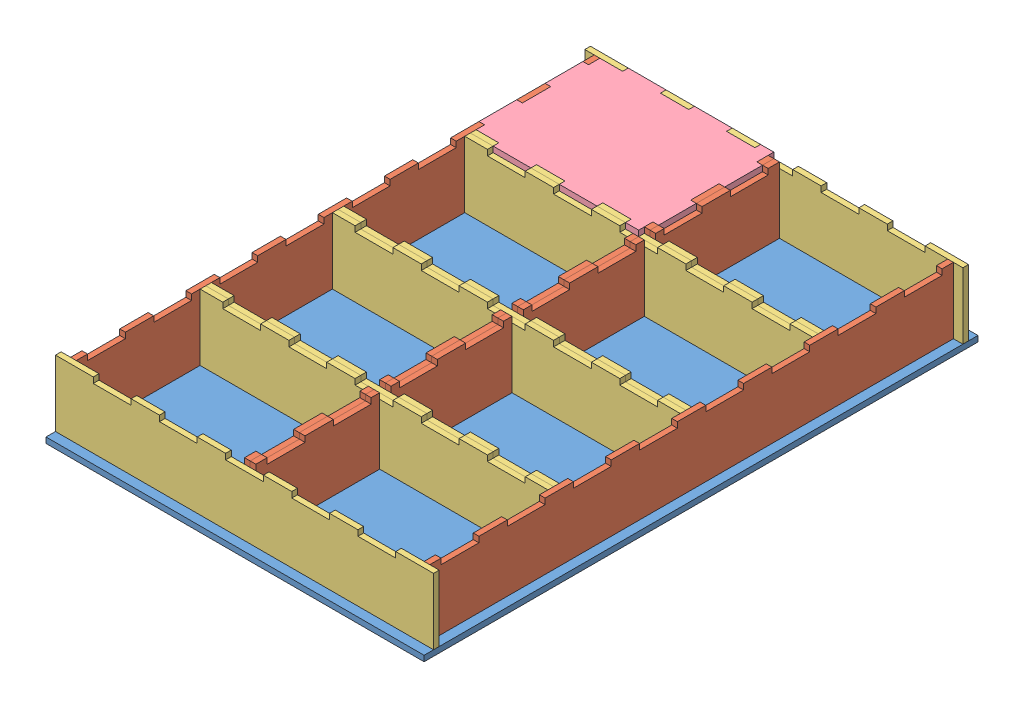
SolidWorks assembly Assem1, configuration Default. Lengths in mm.
Overall size (200 38 293).
20 component instances, 4 part files, 57 mates.
Components (placement in the parent):
- base-1: base [Default] at (16.4212 149.2181 390.9951) size (200 3 293)
- long_side-1: long_side [Default] at (21.4212 152.2181 382.9951) size (3 38 277)
- side-1: side [Default] at (16.4212 152.2181 102.9951) x (1 0 0) z (0 0 -1) size (200 38 3)
- long_side-2: long_side [Default] at (208.4212 152.2181 382.9951) size (3 38 277)
- side-2: side [Default] at (16.4212 152.2181 382.9951) x (1 0 0) z (0 0 -1) size (200 38 3)
- side-3: side [inside] at (208.4212 152.2181 177.4951) x (-1 0 0) z (0 0 1) size (184 38 3)
- side-4: side [inside] at (208.4212 152.2181 174.4951) x (-1 0 0) z (0 0 1) size (184 38 3)
- side-5: side [inside] at (208.4212 152.2181 314.4951) x (-1 0 0) z (0 0 1) size (184 38 3)
- side-6: side [inside] at (208.4212 152.2181 244.4951) x (-1 0 0) z (0 0 1) size (184 38 3)
- side-7: side [inside] at (24.4212 152.2181 244.4951) x (1 0 0) z (0 0 -1) size (184 38 3)
- side-8: side [inside] at (208.4212 152.2181 317.4951) x (-1 0 0) z (0 0 1) size (184 38 3)
- long_side-3: long_side [inside] at (113.4212 152.2181 382.9951) size (3 38 65.5)
- long_side-5: long_side [inside_middle] at (116.4212 152.2181 177.4951) x (-1 0 0) z (0 0 -1) size (3 38 64)
- long_side-7: long_side [inside_middle] at (116.4212 152.2181 241.4951) size (3 38 64)
- long_side-8: long_side [inside_middle] at (116.4212 152.2181 311.4951) size (3 38 64)
- long_side-9: long_side [inside_middle] at (113.4212 152.2181 311.4951) size (3 38 64)
- long_side-10: long_side [inside] at (116.4212 152.2181 382.9951) size (3 38 65.5)
- long_side-11: long_side [inside] at (116.4212 152.2181 105.9951) x (-1 0 0) z (0 0 -1) size (3 38 65.5)
- long_side-12: long_side [inside] at (119.4212 152.2181 105.9951) x (-1 0 0) z (0 0 -1) size (3 38 65.5)
- top-1: top [Default] at (24.4212 184.2181 171.4951) size (95 3 71.5)
Mates (geometry in assembly coordinates):
- Coincident2: coincident anti-aligned: plane of base-1 through (156.4212 142.2181 102.9951) normal (0 0 1); plane of side-1 through (16.4212 152.2181 102.9951) normal (0 0 -1)
- Coincident3: coincident aligned: plane of base-1 through (216.4212 152.2181 390.9951) normal (1 0 0); plane of side-1 through (216.4212 152.2181 105.9951) normal (1 0 0)
- Coincident4: coincident anti-aligned: plane of base-1 through (16.4212 152.2181 390.9951) normal (0 1 0); plane of side-1 through (196.4212 152.2181 105.9951) normal (0 -1 0)
- Coincident5: coincident anti-aligned: plane of base-1 through (24.4212 142.2181 460.9951) normal (-1 0 0); plane of long_side-1 through (24.4212 152.2181 382.9951) normal (1 0 0)
- Coincident6: coincident anti-aligned: plane of long_side-1 through (24.4212 152.2181 105.9951) normal (0 0 -1); plane of side-1 through (16.4212 152.2181 105.9951) normal (0 0 1)
- Coincident7: coincident aligned: plane of base-1 through (16.4212 149.2181 390.9951) normal (0 -1 0); plane of long_side-1 through (24.4212 149.2181 376.9951) normal (0 -1 0)
- Coincident9: coincident aligned: plane of base-1 through (216.4212 152.2181 390.9951) normal (1 0 0); plane of side-2 through (216.4212 152.2181 385.9951) normal (1 0 0)
- Coincident11: coincident aligned: plane of base-1 through (16.4212 149.2181 390.9951) normal (0 -1 0); plane of side-2 through (71.4212 149.2181 385.9951) normal (0 -1 0)
- Coincident14: coincident aligned: plane of base-1 through (16.4212 149.2181 390.9951) normal (0 -1 0); plane of long_side-2 through (211.4212 149.2181 131.9951) normal (0 -1 0)
- Coincident15: coincident anti-aligned: plane of side-1 through (16.4212 152.2181 105.9951) normal (0 0 1); plane of long_side-2 through (211.4212 152.2181 105.9951) normal (0 0 -1)
- Coincident16: coincident anti-aligned: plane of base-1 through (211.4212 142.2181 600.9951) normal (-1 0 0); plane of long_side-2 through (211.4212 152.2181 382.9951) normal (1 0 0)
- Coincident17: coincident anti-aligned: plane of base-1 through (16.4212 152.2181 390.9951) normal (0 1 0); plane of side-3 through (106.4212 152.2181 174.4951) normal (0 -1 0)
- Coincident18: coincident anti-aligned: plane of long_side-2 through (208.4212 152.2181 382.9951) normal (-1 0 0); plane of side-3 through (208.4212 152.2181 174.4951) normal (1 0 0)
- Coincident19: coincident anti-aligned: plane of base-1 through (36.4212 142.2181 177.4951) normal (0 0 -1); plane of side-3 through (208.4212 152.2181 177.4951) normal (0 0 1)
- Coincident20: coincident anti-aligned: plane of base-1 through (16.4212 152.2181 390.9951) normal (0 1 0); plane of side-4 through (208.4212 152.2181 171.4951) normal (0 -1 0)
- Coincident21: coincident anti-aligned: plane of side-3 through (208.4212 152.2181 174.4951) normal (0 0 -1); plane of side-4 through (208.4212 152.2181 174.4951) normal (0 0 1)
- Coincident22: coincident aligned: plane of side-3 through (106.4212 187.2181 174.4951) normal (0 1 0); plane of side-4 through (208.4212 187.2181 171.4951) normal (0 1 0)
- Coincident23: coincident anti-aligned: plane of long_side-2 through (208.4212 152.2181 382.9951) normal (-1 0 0); plane of side-4 through (208.4212 152.2181 171.4951) normal (1 0 0)
- Coincident24: coincident anti-aligned: plane of base-1 through (141.4212 142.2181 247.4951) normal (0 0 -1); plane of side-7 through (24.4212 152.2181 247.4951) normal (0 0 1)
- Coincident25: coincident anti-aligned: plane of base-1 through (16.4212 152.2181 390.9951) normal (0 1 0); plane of side-7 through (91.4212 152.2181 247.4951) normal (0 -1 0)
- Coincident26: coincident anti-aligned: plane of long_side-1 through (24.4212 152.2181 382.9951) normal (1 0 0); plane of side-7 through (24.4212 152.2181 247.4951) normal (-1 0 0)
- Coincident27: coincident aligned: plane of base-1 through (16.4212 149.2181 390.9951) normal (0 -1 0); plane of side-6 through (196.4212 149.2181 241.4951) normal (0 -1 0)
- Coincident28: coincident anti-aligned: plane of side-6 through (208.4212 152.2181 244.4951) normal (0 0 1); plane of side-7 through (24.4212 152.2181 244.4951) normal (0 0 -1)
- Coincident29: coincident anti-aligned: plane of long_side-2 through (208.4212 152.2181 382.9951) normal (-1 0 0); plane of side-6 through (208.4212 152.2181 241.4951) normal (1 0 0)
- Coincident30: coincident anti-aligned: plane of base-1 through (16.4212 152.2181 390.9951) normal (0 1 0); plane of side-5 through (176.4212 152.2181 311.4951) normal (0 -1 0)
- Coincident31: coincident anti-aligned: plane of long_side-2 through (208.4212 152.2181 382.9951) normal (-1 0 0); plane of side-5 through (208.4212 152.2181 311.4951) normal (1 0 0)
- Coincident32: coincident anti-aligned: plane of base-1 through (141.4212 142.2181 311.4951) normal (0 0 1); plane of side-5 through (208.4212 152.2181 311.4951) normal (0 0 -1)
- Coincident33: coincident anti-aligned: plane of base-1 through (16.4212 152.2181 390.9951) normal (0 1 0); plane of side-8 through (141.4212 152.2181 314.4951) normal (0 -1 0)
- Coincident34: coincident anti-aligned: plane of long_side-2 through (208.4212 152.2181 382.9951) normal (-1 0 0); plane of side-8 through (208.4212 152.2181 314.4951) normal (1 0 0)
- Coincident35: coincident anti-aligned: plane of side-5 through (208.4212 152.2181 314.4951) normal (0 0 1); plane of side-8 through (208.4212 152.2181 314.4951) normal (0 0 -1)
- Coincident37: coincident anti-aligned: plane of base-1 through (119.4212 142.2181 286.9951) normal (-1 0 0); plane of long_side-8 through (119.4212 152.2181 311.4951) normal (1 0 0)
- Coincident38: coincident anti-aligned: plane of side-7 through (24.4212 152.2181 247.4951) normal (0 0 1); plane of long_side-8 through (109.4212 192.2181 247.4951) normal (0 0 -1)
- Coincident39: coincident aligned: plane of base-1 through (16.4212 149.2181 390.9951) normal (0 -1 0); plane of long_side-8 through (119.4212 149.2181 271.9951) normal (0 -1 0)
- Coincident40: coincident anti-aligned: plane of long_side-7 through (119.4212 152.2181 241.4951) normal (1 0 0); plane of base-1 through (119.4212 142.2181 216.9951) normal (-1 0 0)
- Coincident41: coincident anti-aligned: plane of side-3 through (208.4212 152.2181 177.4951) normal (0 0 1); plane of long_side-7 through (109.4212 192.2181 177.4951) normal (0 0 -1)
- Coincident42: coincident aligned: plane of long_side-7 through (119.4212 187.2181 216.9951) normal (0 1 0); plane of long_side-8 through (119.4212 187.2181 286.9951) normal (0 1 0)
- Coincident43: coincident anti-aligned: plane of base-1 through (113.4212 142.2181 216.9951) normal (1 0 0); plane of long_side-9 through (113.4212 152.2181 311.4951) normal (-1 0 0)
- Coincident45: coincident aligned: plane of long_side-8 through (119.4212 184.2181 306.9951) normal (0 1 0); plane of long_side-9 through (116.4212 184.2181 306.9951) normal (0 1 0)
- Coincident46: coincident anti-aligned: plane of side-5 through (208.4212 152.2181 311.4951) normal (0 0 -1); plane of long_side-9 through (116.4212 152.2181 311.4951) normal (0 0 1)
- Coincident47: coincident anti-aligned: plane of long_side-5 through (116.4212 152.2181 177.4951) normal (1 0 0); plane of long_side-7 through (116.4212 152.2181 241.4951) normal (-1 0 0)
- Coincident48: coincident anti-aligned: plane of side-6 through (208.4212 152.2181 241.4951) normal (0 0 -1); plane of long_side-5 through (123.4212 192.2181 241.4951) normal (0 0 1)
- Coincident49: coincident aligned: plane of long_side-5 through (113.4212 187.2181 201.9951) normal (0 1 0); plane of long_side-7 through (119.4212 187.2181 216.9951) normal (0 1 0)
- Coincident50: coincident anti-aligned: plane of base-1 through (119.4212 142.2181 321.9951) normal (-1 0 0); plane of long_side-10 through (119.4212 152.2181 382.9951) normal (1 0 0)
- Coincident51: coincident aligned: plane of long_side-9 through (116.4212 187.2181 286.9951) normal (0 1 0); plane of long_side-10 through (119.4212 187.2181 356.9951) normal (0 1 0)
- Coincident52: coincident anti-aligned: plane of side-8 through (208.4212 152.2181 317.4951) normal (0 0 1); plane of long_side-10 through (109.4212 192.2181 317.4951) normal (0 0 -1)
- Coincident53: coincident anti-aligned: plane of long_side-3 through (116.4212 152.2181 382.9951) normal (1 0 0); plane of long_side-10 through (116.4212 152.2181 382.9951) normal (-1 0 0)
- Coincident54: coincident aligned: plane of long_side-3 through (116.4212 187.2181 356.9951) normal (0 1 0); plane of long_side-10 through (119.4212 187.2181 356.9951) normal (0 1 0)
- Coincident55: coincident: plane of side-8 through (208.4212 152.2181 317.4951) normal (0 0 1); moEndPointRef_w of long_side-3
- Coincident56: coincident anti-aligned: plane of base-1 through (113.4212 142.2181 111.9951) normal (1 0 0); plane of long_side-11 through (113.4212 152.2181 105.9951) normal (-1 0 0)
- Coincident57: coincident anti-aligned: plane of side-4 through (208.4212 152.2181 171.4951) normal (0 0 -1); plane of long_side-11 through (123.4212 192.2181 171.4951) normal (0 0 1)
- Coincident58: coincident: line of long_side-5 through (116.4212 187.2181 201.9951) axis (0 0 1); plane of long_side-11 through (113.4212 187.2181 131.9951) normal (0 1 0)
- Coincident59: coincident anti-aligned: plane of side-1 through (16.4212 152.2181 105.9951) normal (0 0 1); plane of long_side-12 through (116.4212 152.2181 105.9951) normal (0 0 -1)
- Coincident60: coincident aligned: plane of long_side-11 through (113.4212 187.2181 131.9951) normal (0 1 0); plane of long_side-12 through (116.4212 187.2181 131.9951) normal (0 1 0)
- Coincident61: coincident anti-aligned: plane of long_side-11 through (116.4212 152.2181 105.9951) normal (1 0 0); plane of long_side-12 through (116.4212 152.2181 105.9951) normal (-1 0 0)
- Coincident62: coincident aligned: plane of side-4 through (71.4212 187.2181 171.4951) normal (0 1 0); plane of top-1 through (24.4212 187.2181 171.4951) normal (0 1 0)
- Coincident63: coincident aligned: plane of long_side-1 through (21.4212 152.2181 382.9951) normal (-1 0 0); plane of top-1 through (21.4212 187.2181 111.9951) normal (-1 0 0)
- Coincident64: coincident aligned: plane of side-1 through (16.4212 152.2181 102.9951) normal (0 0 -1); plane of top-1 through (71.4212 187.2181 102.9951) normal (0 0 -1)
